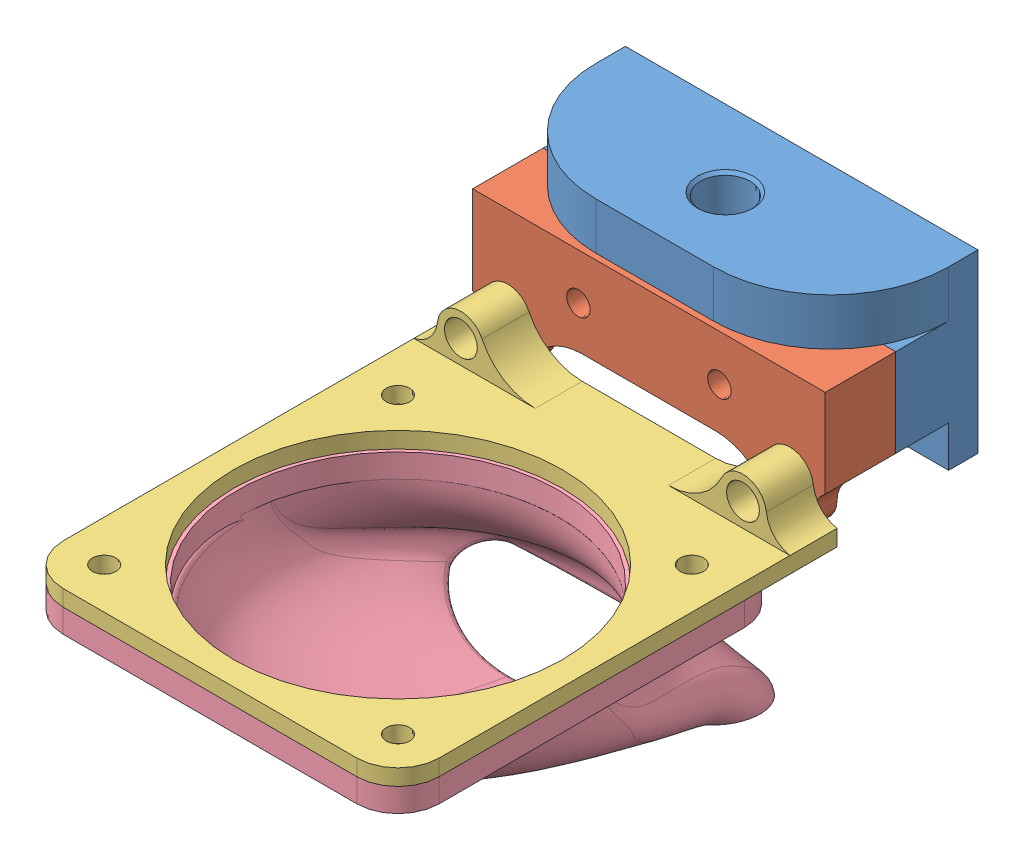
SolidWorks assembly Prusa i3 bowden single, configuration Default. Lengths in mm.
Overall size (64.28 58.3 100.7).
5 component instances, 5 part files, 6 mates.
Components (placement in the parent):
- Back clamp-1: Back clamp [Default] at origin size (60 30 25)
- front clamp-1: front clamp [Default] at (0 0 26) x (-1 0 0) z (0 0 -1) size (60 23.01 12)
- fan support-1: fan support [Default] at (31.4844 -14.7931 26) size (64 14.75 74.7)
- Fan duct-1: Fan duct [Default] at (0 -14.7931 68.7) x (0 0 -1) z (0 1 0) size (77.46 64.28 28.51)
- hex nut style 2_am-3: hex nut style 2_am [B18.2.4.2M - Hex nut, Style 2,  M3 x 0.5 --D-N] at (24 -8.0431 22) size (5.5 6.35 2.9)
Mates (geometry in assembly coordinates):
- Coincidente3: coincident anti-aligned: line of Back clamp-1 through (-30 7 14) axis (0 -1 0); line of front clamp-1 through (-30 -8 14) axis (0 1 0)
- Coincidente5: coincident aligned: circle of fan support-1; circle of Fan duct-1
- Coincidente6: coincident aligned: line of fan support-1 through (-25 -14.7931 100.7) axis (1 0 0); line of Fan duct-1 through (-25 -14.7931 100.7) axis (1 0 0)
- Concentrico2: concentric anti-aligned: circle of front clamp-1; circle of hex nut style 2_am-3
- Coincidente8: coincident anti-aligned: plane of front clamp-1 through (-24 -12.0064 22) normal (0 0 -1); plane of hex nut style 2_am-3 through (24 -4.8677 22) normal (0 0 1)
- Coincidente9: coincident: moEndPointRef_w of front clamp-1; circle of fan support-1
